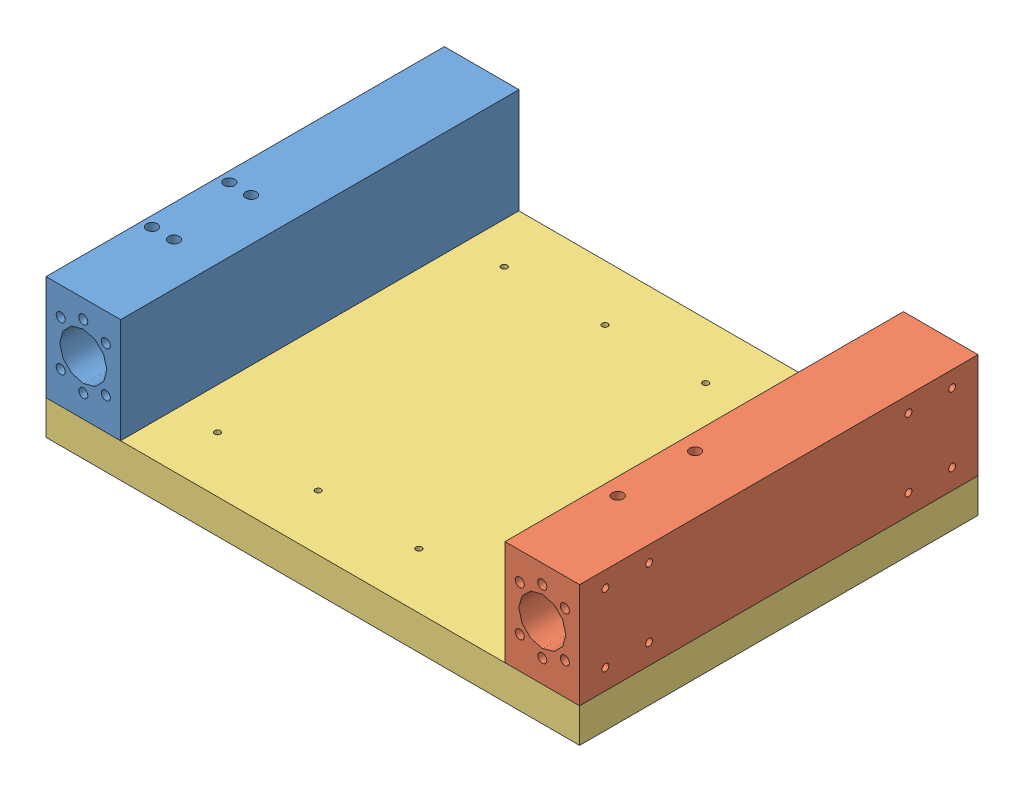
SolidWorks assembly DrillAssembly, configuration Default. Lengths in mm.
Overall size (317.96 82.95 237.38).
3 component instances, 3 part files, 6 mates.
Components (placement in the parent):
- SidingL-1: SidingL [Default] at (11.9274 85.6278 97.0105) size (44.45 62.5 237.38)
- SidingR-1: SidingR [Default] at (285.4367 85.6278 97.0105) size (44.45 62.5 237.38)
- SliderPlate-1: SliderPlate [Default] at (56.407 65.1778 215.7483) size (317.96 20.45 237.28)
Mates (geometry in assembly coordinates):
- Coincident2: coincident anti-aligned: plane of SidingR-1 through (285.4367 85.6278 334.3905) normal (0 -1 0); plane of SliderPlate-1 through (56.407 85.6278 215.7483) normal (0 1 0)
- Coincident4: coincident aligned: plane of SidingR-1 through (285.4367 85.6278 334.3905) normal (0 0 1); plane of SliderPlate-1 through (56.407 85.6278 334.3905) normal (0 0 1)
- Coincident5: coincident aligned: plane of SidingL-1 through (11.9274 85.6278 334.3905) normal (0 0 1); plane of SliderPlate-1 through (56.407 85.6278 334.3905) normal (0 0 1)
- Coincident7: coincident anti-aligned: plane of SidingL-1 through (11.9274 85.6278 334.3905) normal (0 -1 0); plane of SliderPlate-1 through (56.407 85.6278 215.7483) normal (0 1 0)
- Coincident8: coincident aligned: plane of SidingL-1 through (11.9274 85.6278 334.3905) normal (-1 0 0); plane of SliderPlate-1 through (11.9274 85.6278 215.7483) normal (-1 0 0)
- Coincident9: coincident aligned: plane of SidingR-1 through (329.8867 85.6278 334.3905) normal (1 0 0); plane of SliderPlate-1 through (329.8867 85.6278 215.7483) normal (1 0 0)
